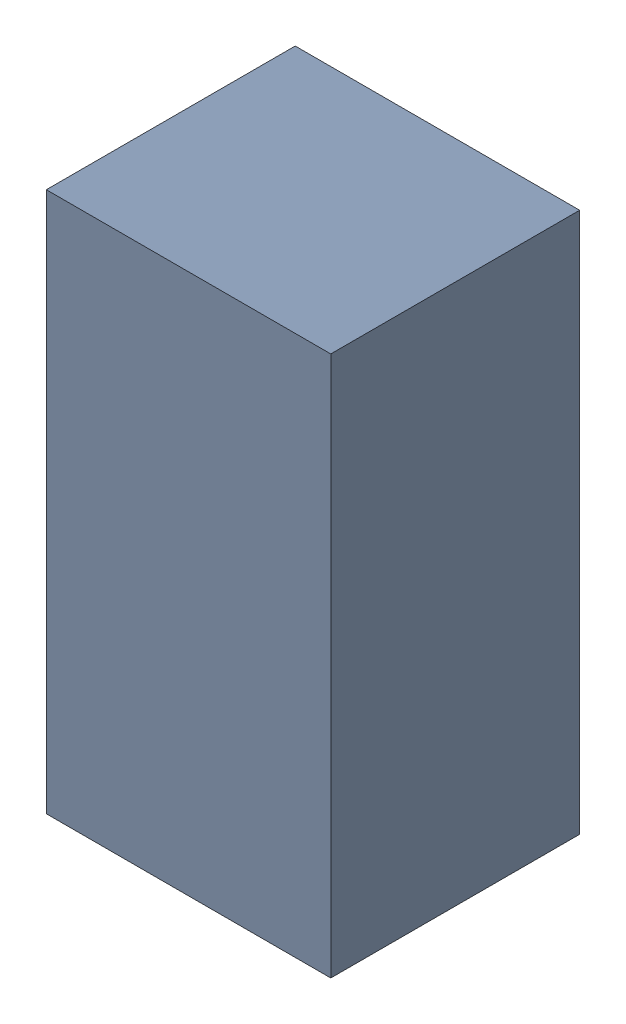
SolidWorks assembly C7_47uF, configuration Default. Lengths in mm.
Overall size (3.05 5.79 2.67).
2 component instances, 1 part files, 0 mates.
Components (placement in the parent):
- 743509024-1: 743509024 [Default] at (197.7136 76.9366 0.127) size (3.05 5.79 2.67)
  - Extruded-1: Extruded [Default] at origin size (3.05 5.79 2.67)
